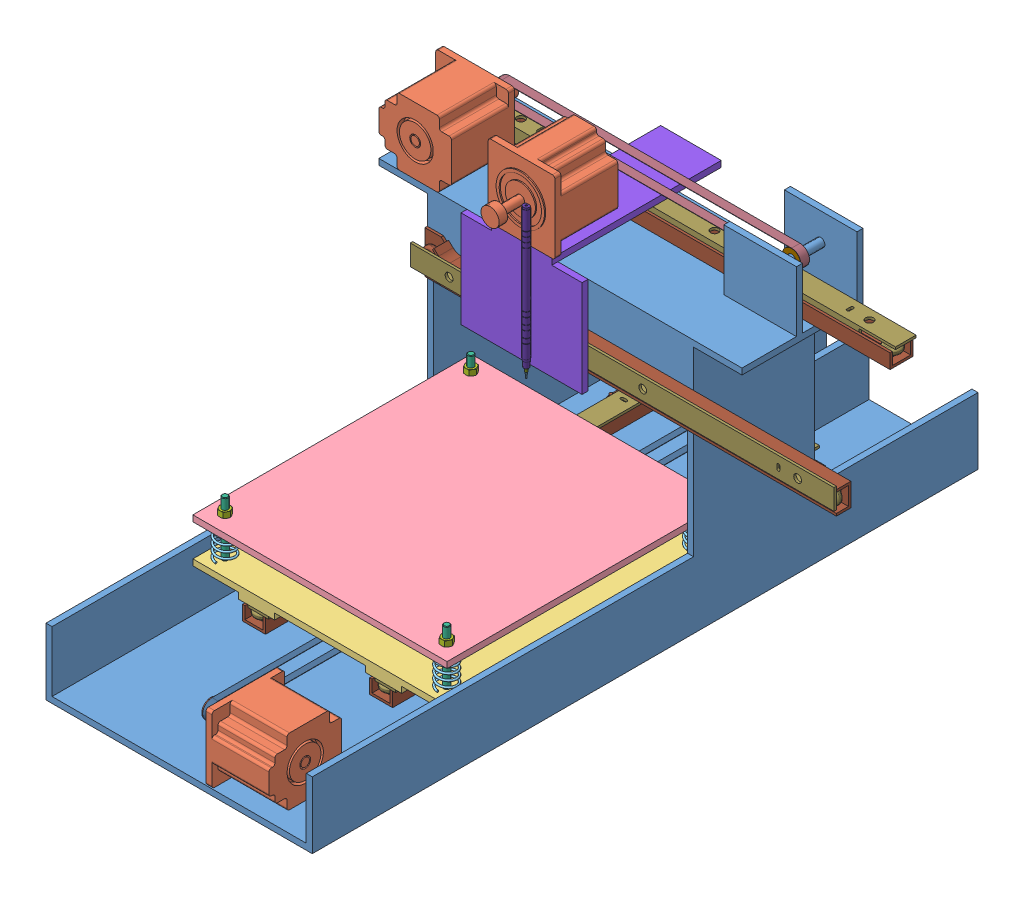
SolidWorks assembly Assem3, configuration Default. Lengths in mm.
Overall size (390 289 550).
46 component instances, 17 part files, 33 mates.
Components (placement in the parent):
- Part1-1: Part1 [Default] at (-23.4944 -153.0935 28.087) size (300 260 550)
- part 8-1: part 8 [Default] at (-140.9944 84.4065 -58.913) x (-1 0 0) z (0 0 1) size (60 55 78)
- part 8-2: part 8 [Default] at (3.6654 -120.5935 270.587) x (0 0 1) z (1 0 0) size (60 55 78)
- Assem1-1: Assem1 [Default] at (-4.0334 -128.3463 54.8864) x (0 0 -1) z (-1 0 0) size (230 55 210)
  - Part4-1: Part4 [Default] at (-116.887 -20.5528 -75.9837) size (230 10 210)
  - Part3-1: Part3 [Default] at (29.2094 -47.0514 4.8523) x (0 0 -1) z (-1 0 0) size (210 5 230)
  - Part5-1: Part5 [Default] at (-118.7637 -46.3117 -72.2056) size (16.52 28.04 16.52)
  - Part5-2: Part5 [Default] at (-118.3534 -46.3117 111.3835) size (16.52 28.04 16.52)
  - Part5-3: Part5 [Default] at (86.0231 -46.3117 -73.8497) size (16.52 28.04 16.52)
  - Part5-4: Part5 [Default] at (85.0495 -46.3117 111.6262) size (16.52 28.04 16.52)
  - socket countersunk head screw_am-5: socket countersunk head screw_am [B18.3.5M - 5 x 0.8 x 50 Socket FCHS  -- 50N] at (-118.3534 -15.5528 111.3835) x (0 -1 0) z (0 0 1) size (50 9.75 9.75)
  - socket countersunk head screw_am-6: socket countersunk head screw_am [B18.3.5M - 5 x 0.8 x 50 Socket FCHS  -- 50N] at (85.0495 -15.5528 111.6262) x (0 -1 0) z (0 0 1) size (50 9.75 9.75)
  - socket countersunk head screw_am-7: socket countersunk head screw_am [B18.3.5M - 5 x 0.8 x 50 Socket FCHS  -- 50N] at (86.0231 -15.5528 -73.8497) x (0 -1 0) z (0 0 1) size (50 9.75 9.75)
  - socket countersunk head screw_am-8: socket countersunk head screw_am [B18.3.5M - 5 x 0.8 x 50 Socket FCHS  -- 50N] at (-118.7637 -15.5528 -72.2056) x (0 -1 0) z (0.680287 0 0.732946) size (50 9.75 9.75)
  - hex nut style 1_am-1: hex nut style 1_am [B18.2.4.1M - Hex nut, Style 1,  M5 x 0.8 --D-N] at (86.0231 -56.7514 -73.8497) x (1 0 0) z (0 -1 0) size (8 9.24 4.7)
  - hex nut style 1_am-2: hex nut style 1_am [B18.2.4.1M - Hex nut, Style 1,  M5 x 0.8 --D-N] at (-118.7637 -56.7514 -72.2056) x (1 0 0) z (0 -1 0) size (8 9.24 4.7)
  - hex nut style 1_am-3: hex nut style 1_am [B18.2.4.1M - Hex nut, Style 1,  M5 x 0.8 --D-N] at (-118.3534 -56.7514 111.3835) x (1 0 0) z (0 -1 0) size (8 9.24 4.7)
  - hex nut style 1_am-4: hex nut style 1_am [B18.2.4.1M - Hex nut, Style 1,  M5 x 0.8 --D-N] at (85.0495 -56.7514 111.6262) x (1 0 0) z (0 -1 0) size (8 9.24 4.7)
- Assem4-1: Assem4 [Default] at (-34.3622 62.8808 -72.1691) x (0 0 -1) z (1 0 0) size (166 145 100)
  - Part9-1: Part9 [Default] at (-9.2562 8.0256 -2.2666) size (140 85 100)
  - part 8-1: part 8 [Default] at (-74.2562 40.5256 -2.256) x (0 1 0) z (1 0 0) size (60 55 78)
- Part10-1: Part10 [Default] at (96.5056 84.4065 -89.913) x (-0.999128 0.041756 0) z (0 0 1) size (15 15 7)
- Part10-2: Part10 [Default] at (-27.3346 -120.5935 -216.913) x (0 0.044454 -0.999011) z (1 0 0) size (15 15 7)
- chain-1: chain [Default] at (-21.3183 -115.4609 8.925) x (0 0 1) z (-1 0 0) size (505.6 15.6 5)
- Both Rails (R)-1: Both Rails (R) [Default] at (50.1126 -158.093 -163.566) x (0 0 1) z (0 -1 0) size (350 35 14)
  - Cabinet Rail (R)-1: Cabinet Rail (R) [Default] at (0.3083 6.107 -6.2995) size (350 35 12)
  - Drawer Rail (R)-1: Drawer Rail (R) [Default] at (87.0565 11.107 -62.2995) size (350 19 12)
    - Drawer Rail (R)-1: Drawer Rail (R) [Default] at origin size (350 19 12)
- Both Rails (R)-2: Both Rails (R) [Default] at (-54.8874 -158.093 -163.566) x (0 0 1) z (0 -1 0) size (350 35 14)
  - Cabinet Rail (R)-1: Cabinet Rail (R) [Default] at (0.3083 6.107 -6.2995) size (350 35 12)
  - Drawer Rail (R)-1: Drawer Rail (R) [Default] at (87.0565 11.107 -62.2995) size (350 19 12)
    - Drawer Rail (R)-1: Drawer Rail (R) [Default] at origin size (350 19 12)
- Both Rails (R)-3: Both Rails (R) [Default] at (-161.4775 30.607 -104.5472) x (1 0 0) z (0 -1 0) size (350 35 14)
  - Cabinet Rail (R)-1: Cabinet Rail (R) [Default] at (0.3083 6.107 -6.2995) size (350 35 12)
  - Drawer Rail (R)-1: Drawer Rail (R) [Default] at (87.0565 11.107 -62.2995) size (350 19 12)
    - Drawer Rail (R)-1: Drawer Rail (R) [Default] at origin size (350 19 12)
- Both Rails (R)-4: Both Rails (R) [Default] at (-133.8027 34.5134 -38.2125) x (1 0 0) z (0 0 -1) size (350 35 14)
  - Cabinet Rail (R)-1: Cabinet Rail (R) [Default] at (0.3083 6.107 -6.2995) size (350 35 12)
  - Drawer Rail (R)-1: Drawer Rail (R) [Default] at (87.0565 11.107 -62.2995) size (350 19 12)
    - Drawer Rail (R)-1: Drawer Rail (R) [Default] at origin size (350 19 12)
- chain 2-1: chain 2 [Default] at (92.7556 84.4065 -89.913) size (255.6 15.6 7)
- pen-1: pen [Default] at (-32.4715 -11.588 15.3261) x (1 0 0) z (0 0 -1) size (5.5 123.91 5.5)
  - nib-1: nib [Default] at (2.5418 -0.4671 5.4891) size (1.49 6.65 1.49)
  - nibball-1: nibball [Default] at (2.5418 6.1329 5.4891) x (1 0 0) z (0 -1 0) size (0.59 0.59 0.59)
  - nibbody-1: nibbody [Default] at (2.5418 -3.9671 5.4891) size (3 5.49 3)
  - penbody-1: penbody [Default] at (2.5418 -117.4771 5.4891) size (5.5 115.5 5.5)
Mates (geometry in assembly coordinates):
- Coincident1: coincident anti-aligned: plane of Part1-1 through (-23.4944 56.9065 28.087) normal (0 1 0); plane of part 8-1 through (-156.4944 56.9065 -11.913) normal (0 -1 0)
- Coincident2: coincident aligned: plane of Part1-1 through (-173.4944 56.9065 -111.913) normal (-1 0 0); plane of part 8-1 through (-173.4944 76.4065 -11.913) normal (-1 0 0)
- Coincident3: coincident aligned: plane of Part1-1 through (81.5056 51.9065 -11.913) normal (0 0 1); plane of part 8-1 through (-121.4944 64.9065 -11.913) normal (0 0 1)
- Parallel1: parallel: plane of Part1-1 through (81.5056 -98.0935 -246.913) normal (-1 0 0); plane of part 8-2 through (50.6654 -140.0935 251.087) normal (1 0 0)
- Coincident5: coincident: plane of Part1-1 through (86.5056 -148.0935 303.087) normal (0 0 1); plane of part 8-2 through (50.6654 -128.5935 303.087) normal (0 0 1)
- Coincident6: coincident anti-aligned: plane of Part1-1 through (-23.4944 -148.0935 28.087) normal (0 1 0); plane of part 8-2 through (50.6654 -148.0935 286.087) normal (0 -1 0)
- Coincident9: coincident anti-aligned: plane of Part1-1 through (-128.4944 -98.0935 -246.913) normal (1 0 0); plane of Assem1-1/Part4-1 through (-128.4944 -112.7935 186.7423) normal (-1 0 0)
- Parallel4: parallel anti-aligned: plane of Part1-1 through (81.5056 51.9065 -11.913) normal (0 0 1); plane of Assem4-1/Part9-1 through (-36.6288 70.9065 2.087) normal (0 0 -1)
- Concentric1: concentric anti-aligned: cylinder of Part1-1 through (96.5056 84.4065 -109.913) axis (0 0 1) radius 3.5; cylinder of Part10-1 through (96.5056 84.4065 -82.913) axis (0 0 -1) radius 3.5
- Concentric2: concentric anti-aligned: cylinder of Part1-1 through (-39.4944 -120.5935 -216.913) axis (1 0 0) radius 3.5; cylinder of Part10-2 through (-20.3346 -120.5935 -216.913) axis (-1 0 0) radius 3.5
- Coincident16: coincident aligned: plane of part 8-1 through (-143.4944 84.4065 -89.913) normal (0 0 -1); plane of Part10-1 through (96.5056 84.4065 -89.913) normal (0 0 -1)
- Coincident17: coincident aligned: plane of part 8-2 through (-20.3346 -120.5935 273.087) normal (1 0 0); plane of Part10-2 through (-20.3346 -120.5935 -216.913) normal (1 0 0)
- Concentric4: concentric anti-aligned: cylinder of part 8-2 through (-20.3346 -120.5935 273.087) axis (-1 0 0) radius 7.5; cylinder of chain-1 through (-26.3183 -120.5935 273.087) axis (1 0 0) radius 7.5
- Concentric5: concentric anti-aligned: cylinder of Part10-2 through (-20.3346 -120.5935 -216.913) axis (-1 0 0) radius 7.5; cylinder of chain-1 through (-26.3183 -120.5935 -216.913) axis (1 0 0) radius 7.5
- Parallel5: parallel anti-aligned: plane of Assem1-1/Part4-1 through (71.9503 -112.7935 171.7734) normal (0 -1 0); plane of chain-1 through (-26.3183 -112.7935 -216.913) normal (0 1 0)
- Parallel6: parallel anti-aligned: plane of Part1-1 through (-23.4944 -148.0935 28.087) normal (0 1 0); plane of Assem1-1/Part4-1 through (71.9503 -112.7935 171.7734) normal (0 -1 0)
- Coincident23: coincident anti-aligned: plane of Assem1-1/Part4-1 through (71.9503 -112.7935 171.7734) normal (0 -1 0); plane of chain-1 through (-26.3183 -112.7935 -216.913) normal (0 1 0)
- Coincident26: coincident anti-aligned: plane of Assem1-1/Part4-1 through (71.9503 -117.7935 171.7734) normal (0 -1 0); plane of Both Rails (R)-2/Drawer Rail (R)-1/Drawer Rail (R)-1 through (-65.9944 -117.7935 -76.5096) normal (0 1 0)
- Coincident28: coincident aligned: plane of Assem1-1/Part4-1 through (-60.9944 -117.7935 171.7734) normal (1 0 0); plane of Both Rails (R)-2/Cabinet Rail (R)-1 through (-60.9944 -129.7935 -163.2577) normal (1 0 0)
- Coincident29: coincident aligned: plane of Assem1-1/Part4-1 through (44.0056 -117.7935 186.7423) normal (1 0 0); plane of Both Rails (R)-1/Cabinet Rail (R)-1 through (44.0056 -129.7935 -163.2577) normal (1 0 0)
- Coincident30: coincident aligned: plane of Assem1-1/Part4-1 through (81.5056 -112.7935 186.7423) normal (0 0 1); plane of Both Rails (R)-2/Cabinet Rail (R)-1 through (-70.4944 -129.7935 186.7423) normal (0 0 1)
- Coincident31: coincident aligned: plane of Assem1-1/Part4-1 through (81.5056 -112.7935 186.7423) normal (0 0 1); plane of Both Rails (R)-1/Cabinet Rail (R)-1 through (34.5056 -129.7935 186.7423) normal (0 0 1)
- Coincident32: coincident anti-aligned: plane of Assem1-1/Part4-1 through (71.9503 -117.7935 171.7734) normal (0 -1 0); plane of Both Rails (R)-1/Drawer Rail (R)-1/Drawer Rail (R)-1 through (39.0056 -117.7935 -76.5096) normal (0 1 0)
- Coincident34: coincident anti-aligned: plane of Part1-1 through (81.5056 51.9065 -11.913) normal (0 0 1); plane of Both Rails (R)-4/Cabinet Rail (R)-1 through (-133.4944 28.4065 -11.913) normal (0 0 -1)
- Coincident35: coincident anti-aligned: plane of Assem4-1/Part9-1 through (-36.6288 70.9065 2.087) normal (0 0 -1); plane of Both Rails (R)-4/Drawer Rail (R)-1/Drawer Rail (R)-1 through (-46.7462 23.4065 2.087) normal (0 0 1)
- Coincident36: coincident aligned: plane of Part1-1 through (-133.4944 -148.0935 -246.913) normal (-1 0 0); plane of Both Rails (R)-4/Cabinet Rail (R)-1 through (-133.4944 28.4065 -9.913) normal (-1 0 0)
- Concentric6: concentric aligned: cylinder of part 8-1 through (-143.4944 84.4065 -82.913) axis (0 0 -1) radius 7.5; cylinder of chain 2-1 through (-143.4944 84.4065 -82.913) axis (0 0 -1) radius 7.5
- Concentric7: concentric aligned: cylinder of Part10-1 through (96.5056 84.4065 -82.913) axis (0 0 -1) radius 7.5; cylinder of chain 2-1 through (96.5056 84.4065 -82.913) axis (0 0 -1) radius 7.5
- Coincident37: coincident aligned: plane of Part10-1 through (96.5056 84.4065 -82.913) normal (0 0 1); plane of chain 2-1 through (-143.4944 84.4065 -82.913) normal (0 0 1)
- Coincident39: coincident anti-aligned: plane of Part1-1 through (-23.4944 56.9065 28.087) normal (0 1 0); plane of Both Rails (R)-3/Cabinet Rail (R)-1 through (-161.1692 56.9065 -98.4402) normal (0 -1 0)
- Coincident40: coincident anti-aligned: plane of Assem4-1/Part9-1 through (-36.6288 70.9065 -62.913) normal (0 -1 0); plane of Both Rails (R)-3/Drawer Rail (R)-1/Drawer Rail (R)-1 through (-74.4211 70.9065 -93.4402) normal (0 1 0)
- Tangent1: tangent anti-aligned: plane of Assem4-1/Part9-1 through (-61.6288 75.9065 7.087) normal (0 0 1); cylinder of pen-1/penbody-1 through (-29.9297 31.8891 9.837) axis (0 1 0) radius 2.75
- Coincident41: coincident aligned: plane of Part1-1 through (-128.4944 1.9065 -16.913) normal (0 -1 0); plane of Both Rails (R)-4/Cabinet Rail (R)-1 through (216.5056 1.9065 -9.913) normal (0 -1 0)
